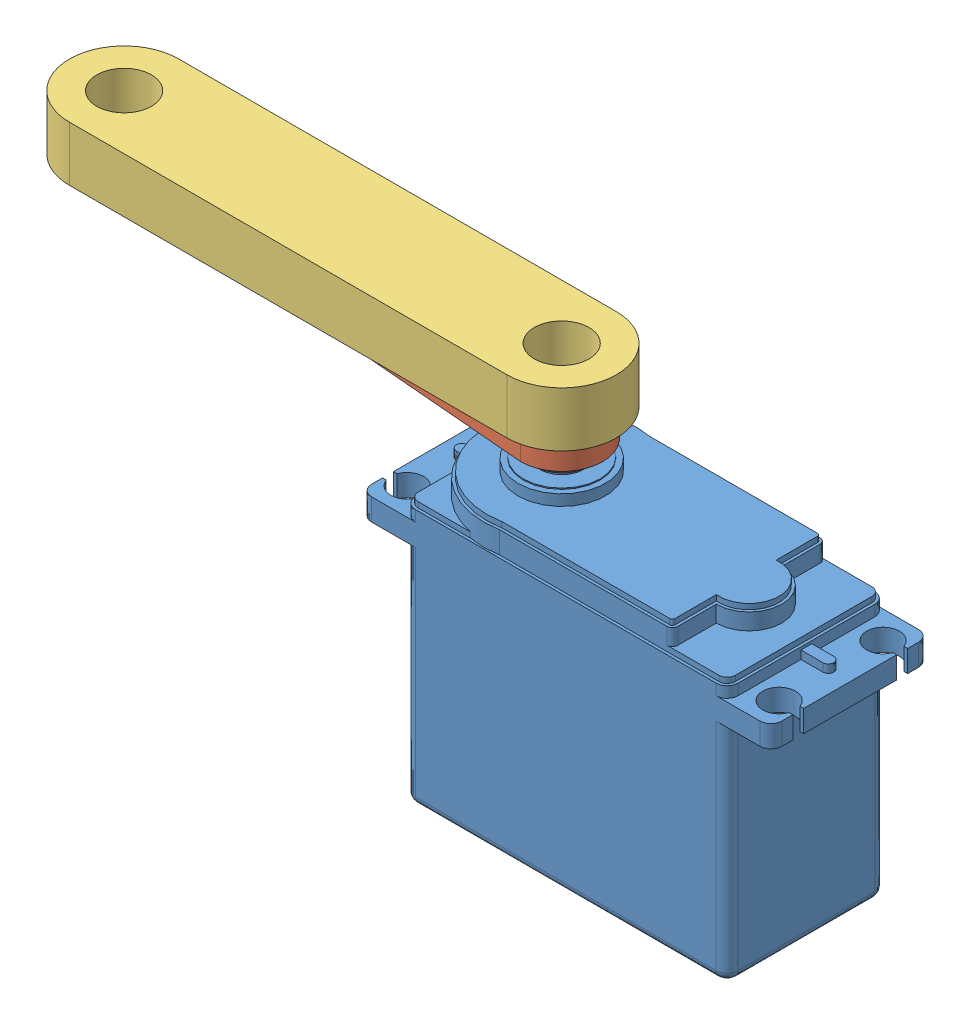
SolidWorks assembly ServoLink, configuration Default. Lengths in mm.
Overall size (142.75 72.2 29).
3 component instances, 3 part files, 6 mates.
Components (placement in the parent):
- Servo body-1: Servo body [Default] at (20.9549 7.063 62.6266) size (75 60.2 29)
- Servo arm-1: Servo arm [Default] at (5.7049 64.263 62.6266) x (0 0 -1) z (1 0 0) size (15 8 42.5)
- Link-1: Link [Default] at (-34.2951 69.263 62.6266) x (-1 0 0) z (0 -1 0) size (100 20 10)
Mates (geometry in assembly coordinates):
- Concentric1: concentric anti-aligned: cylinder of Servo body-1 through (5.7049 67.263 62.6266) axis (0 -1 0) radius 4; cylinder of Servo arm-1 through (5.7049 64.263 62.6266) axis (0 1 0) radius 4
- Coincident1: coincident anti-aligned: plane of Servo body-1 through (5.7049 67.263 62.6266) normal (0 1 0); plane of Servo arm-1 through (5.7049 67.263 62.6266) normal (0 -1 0)
- LimitAngle1: limit planar angle = 3.141593 rad aligned: plane of Servo body-1 through (20.9549 7.063 62.6266) normal (0 0 1); plane of Servo arm-1 through (5.7049 64.263 62.6266) normal (0 0 -1)
- Concentric2: concentric anti-aligned: cylinder of Servo body-1 through (5.7049 63.263 62.6266) axis (0 1 0) radius 2; cylinder of Link-1 through (5.7049 79.263 62.6266) axis (0 -1 0) radius 5
- Coincident3: coincident anti-aligned: plane of Servo arm-1 through (5.7049 69.263 62.6266) normal (0 1 0); plane of Link-1 through (5.7049 69.263 62.6266) normal (0 -1 0)
- Angle2: planar angle = 0 rad aligned: plane of Link-1 through (-34.2951 69.263 62.6266) normal (0 0 -1); plane of Servo arm-1 through (5.7049 64.263 62.6266) normal (0 0 -1)
